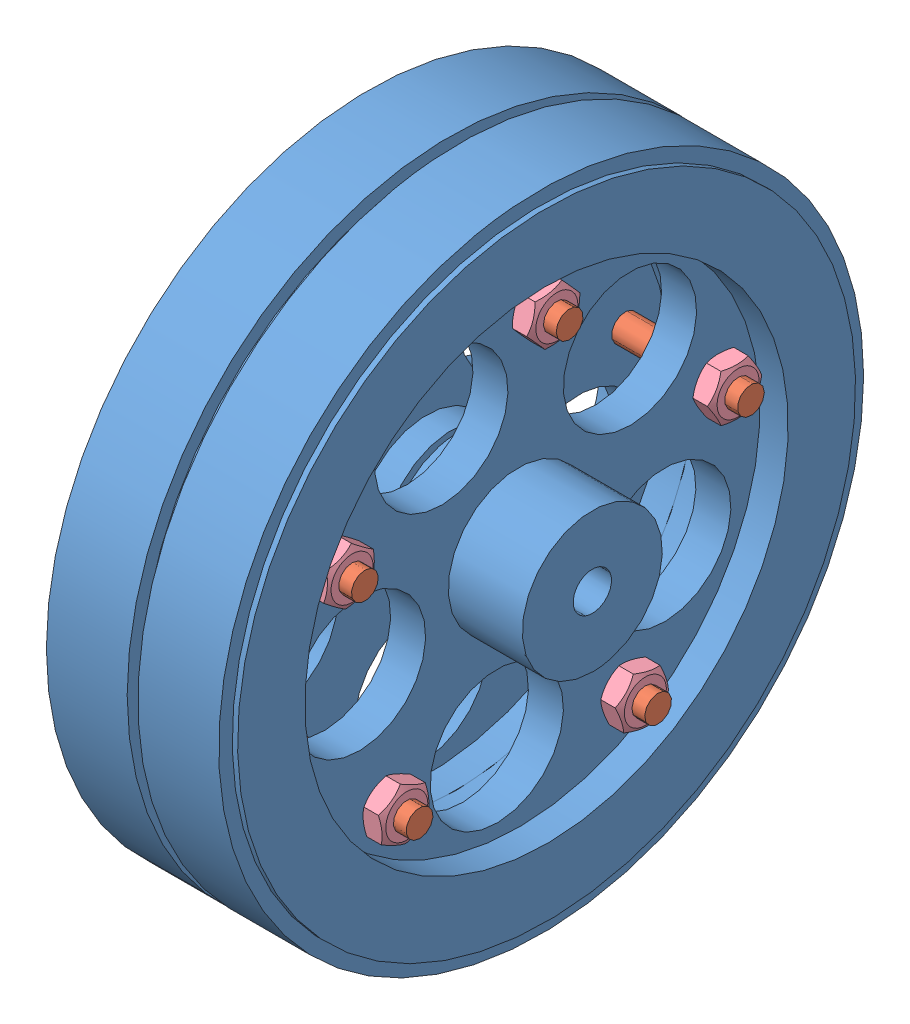
SolidWorks assembly MACM010300_DrivingWheel, configuration 默认. Lengths in mm.
Overall size (40.8 108.78 108.78).
17 component instances, 4 part files, 9 mates.
Components (placement in the parent):
- MACM010301_DrivingWheel-1: MACM010301_DrivingWheel [默认] at (-30.5506 -9.9077 91.7141) size (20.4 95.8 95.8)
- MACM010301_DrivingWheel-2: MACM010301_DrivingWheel [默认] at (-16.9506 -9.9077 91.7141) x (-1 0 0) z (0 -0.989252 -0.146219) size (20.4 95.8 95.8)
- GB_CROSS_SCREWS_TYPE1 M4X25-25  H type-N-1: GB_CROSS_SCREWS_TYPE1 M4X25-25  H type-N [GB_CROSS_SCREWS_TYPE1 M4X25-25  H type-N] at (-37.3506 -2.9981 62.2638) size (28.07 8 8)
- GB_FASTENER_WASHER_SW 4-1: GB_FASTENER_WASHER_SW 4 [GB_FASTENER_WASHER_SW 4] at (-33.1506 -2.9981 62.2638) x (0 0 -1) z (1 0 0) size (6.6 6.6 1.1)
- GB_FASTENER_NUT_SNAB1 M4-N-1: GB_FASTENER_NUT_SNAB1 M4-N [GB_FASTENER_NUT_SNAB1 M4-N] at (-14.3506 -2.9981 62.2638) x (0 0 1) z (-1 0 0) size (8.08 7 3.2)
- GB_FASTENER_NUT_SNAB1 M4-N-2: GB_FASTENER_NUT_SNAB1 M4-N [GB_FASTENER_NUT_SNAB1 M4-N] at (-14.3506 -35.7814 76.042) x (0 0.951057 0.309017) z (-1 0 0) size (8.08 7 3.2)
- GB_FASTENER_NUT_SNAB1 M4-N-3: GB_FASTENER_NUT_SNAB1 M4-N [GB_FASTENER_NUT_SNAB1 M4-N] at (-14.3506 -32.8082 111.4785) x (0 0.587785 -0.809017) z (-1 0 0) size (8.08 7 3.2)
- GB_FASTENER_NUT_SNAB1 M4-N-4: GB_FASTENER_NUT_SNAB1 M4-N [GB_FASTENER_NUT_SNAB1 M4-N] at (-14.3506 1.8127 119.6012) x (0 -0.587785 -0.809017) z (-1 0 0) size (8.08 7 3.2)
- GB_FASTENER_NUT_SNAB1 M4-N-5: GB_FASTENER_NUT_SNAB1 M4-N [GB_FASTENER_NUT_SNAB1 M4-N] at (-14.3506 20.2364 89.1849) x (0 -0.951057 0.309017) z (-1 0 0) size (8.08 7 3.2)
- GB_FASTENER_WASHER_SW 4-2: GB_FASTENER_WASHER_SW 4 [GB_FASTENER_WASHER_SW 4] at (-33.1506 -35.7814 76.042) x (0 -0.951057 -0.309017) z (1 0 0) size (6.6 6.6 1.1)
- GB_FASTENER_WASHER_SW 4-3: GB_FASTENER_WASHER_SW 4 [GB_FASTENER_WASHER_SW 4] at (-33.1506 -32.8082 111.4785) x (0 -0.587785 0.809017) z (1 0 0) size (6.6 6.6 1.1)
- GB_FASTENER_WASHER_SW 4-4: GB_FASTENER_WASHER_SW 4 [GB_FASTENER_WASHER_SW 4] at (-33.1506 1.8127 119.6012) x (0 0.587785 0.809017) z (1 0 0) size (6.6 6.6 1.1)
- GB_FASTENER_WASHER_SW 4-5: GB_FASTENER_WASHER_SW 4 [GB_FASTENER_WASHER_SW 4] at (-33.1506 20.2364 89.1849) x (0 0.951057 -0.309017) z (1 0 0) size (6.6 6.6 1.1)
- GB_CROSS_SCREWS_TYPE1 M4X25-25  H type-N-2: GB_CROSS_SCREWS_TYPE1 M4X25-25  H type-N [GB_CROSS_SCREWS_TYPE1 M4X25-25  H type-N] at (-37.3506 -35.7814 76.042) x (1 0 0) z (0 0.951057 0.309017) size (28.07 8 8)
- GB_CROSS_SCREWS_TYPE1 M4X25-25  H type-N-3: GB_CROSS_SCREWS_TYPE1 M4X25-25  H type-N [GB_CROSS_SCREWS_TYPE1 M4X25-25  H type-N] at (-37.3506 -32.8082 111.4785) x (1 0 0) z (0 0.587785 -0.809017) size (28.07 8 8)
- GB_CROSS_SCREWS_TYPE1 M4X25-25  H type-N-4: GB_CROSS_SCREWS_TYPE1 M4X25-25  H type-N [GB_CROSS_SCREWS_TYPE1 M4X25-25  H type-N] at (-37.3506 1.8127 119.6012) x (1 0 0) z (0 -0.587785 -0.809017) size (28.07 8 8)
- GB_CROSS_SCREWS_TYPE1 M4X25-25  H type-N-5: GB_CROSS_SCREWS_TYPE1 M4X25-25  H type-N [GB_CROSS_SCREWS_TYPE1 M4X25-25  H type-N] at (-37.3506 20.2364 89.1849) x (1 0 0) z (0 -0.951057 0.309017) size (28.07 8 8)
Mates (geometry in assembly coordinates):
- 重合1: coincident anti-aligned: plane of MACM010301_DrivingWheel-1 through (-23.7506 -9.9077 91.7141) normal (1 0 0); plane of MACM010301_DrivingWheel-2 through (-23.7506 -9.9077 91.7141) normal (-1 0 0)
- 同心1: concentric anti-aligned: cylinder of MACM010301_DrivingWheel-1 through (-44.1506 20.2364 89.1849) axis (1 0 0) radius 1.8; cylinder of MACM010301_DrivingWheel-2 through (-3.3506 20.2364 89.1849) axis (-1 0 0) radius 1.8
- 同心2: concentric anti-aligned: cylinder of MACM010301_DrivingWheel-1 through (-37.3506 -9.9077 91.7141) axis (1 0 0) radius 2.85; cylinder of MACM010301_DrivingWheel-2 through (-10.1506 -9.9077 91.7141) axis (-1 0 0) radius 2.85
- 同心3: concentric aligned: cylinder of MACM010301_DrivingWheel-1 through (-44.1506 -2.9981 62.2638) axis (1 0 0) radius 1.8; cylinder of GB_CROSS_SCREWS_TYPE1 M4X25-25  H type-N-1 through (-32.8348 -2.9981 62.2638) axis (1 0 0) radius 2
- 同心4: concentric aligned: cylinder of GB_CROSS_SCREWS_TYPE1 M4X25-25  H type-N-1 through (-32.8348 -2.9981 62.2638) axis (1 0 0) radius 2; cylinder of GB_FASTENER_WASHER_SW 4-1 through (-34.2506 -2.9981 62.2638) axis (1 0 0) radius 2.2
- 重合2: coincident anti-aligned: plane of GB_CROSS_SCREWS_TYPE1 M4X25-25  H type-N-1 through (-34.2506 -0.6481 62.2638) normal (1 0 0); plane of GB_FASTENER_WASHER_SW 4-1 through (-34.2506 -2.9981 62.2638) normal (-1 0 0)
- 重合3: coincident anti-aligned: plane of MACM010301_DrivingWheel-1 through (-33.1506 -9.9077 91.7141) normal (-1 0 0); plane of GB_FASTENER_WASHER_SW 4-1 through (-33.1506 -2.9981 62.2638) normal (1 0 0)
- 同心5: concentric anti-aligned: cylinder of GB_CROSS_SCREWS_TYPE1 M4X25-25  H type-N-1 through (-32.8348 -2.9981 62.2638) axis (1 0 0) radius 2; cylinder of GB_FASTENER_NUT_SNAB1 M4-N-1 through (-11.1506 -2.9981 62.2638) axis (-1 0 0) radius 1.621
- 重合4: coincident anti-aligned: plane of MACM010301_DrivingWheel-2 through (-14.3506 -9.9077 91.7141) normal (1 0 0); plane of GB_FASTENER_NUT_SNAB1 M4-N-1 through (-14.3506 -2.9981 66.3052) normal (-1 0 0)
